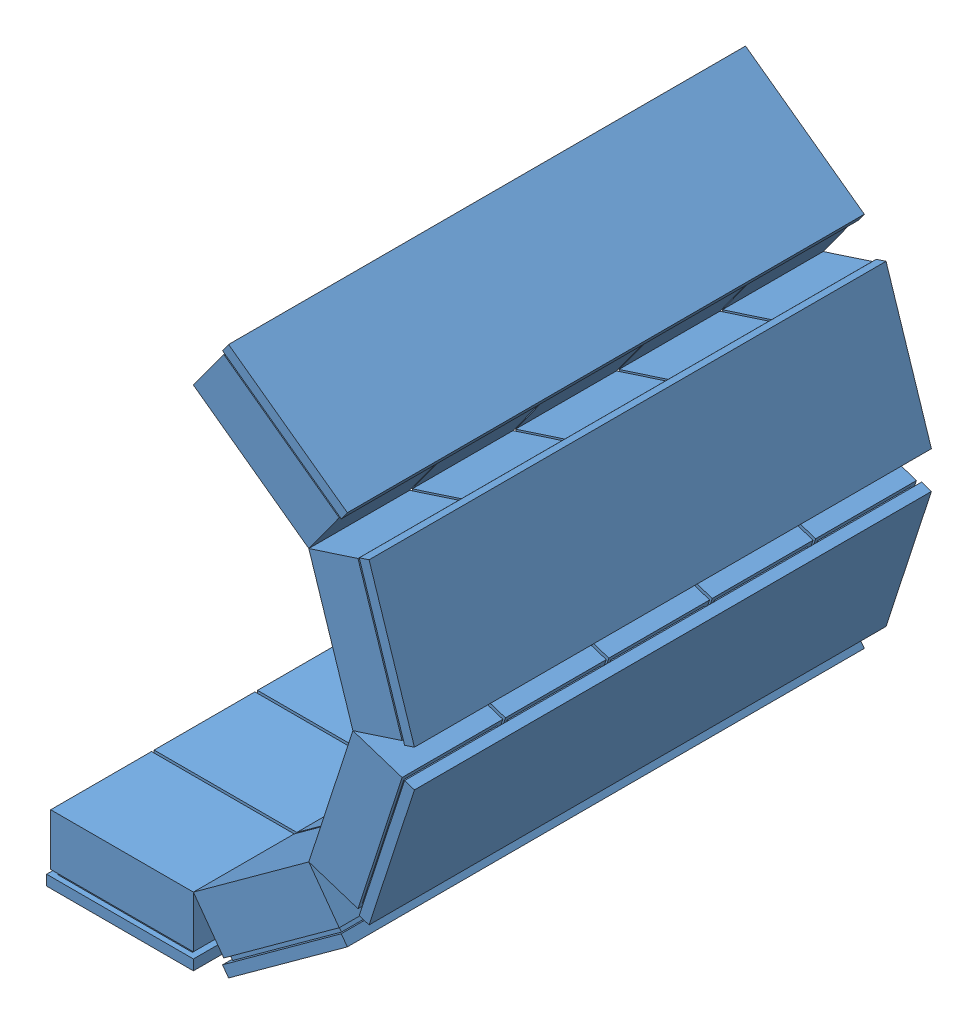
SolidWorks assembly CshapedDetector, configuration Default. Lengths in mm.
Overall size (177.89 270.84 250).
5 component instances, 1 part files, 14 mates.
Components (placement in the parent):
- 1Detector-1: 1Detector [Default] at (91.8512 126.8436 184.2598) size (71 32 250)
- 1Detector-2: 1Detector [Default] at (173.0714 153.2337 184.2598) x (0.809017 0.587785 0) z (0 0 1) size (71 32 250)
- 1Detector-4: 1Detector [Default] at (223.2683 222.3237 184.2598) x (0.309017 0.951057 0) z (0 0 1) size (71 32 250)
- 1Detector-5: 1Detector [Default] at (223.2683 307.7237 184.2598) x (-0.309017 0.951057 0) z (0 0 1) size (71 32 250)
- 1Detector-6: 1Detector [Default] at (173.0714 376.8138 184.2598) x (-0.809017 0.587785 0) z (0 0 1) size (71 32 250)
Mates (geometry in assembly coordinates):
- Coincident2: coincident: line of 1Detector-1 through (126.3512 158.8436 308.2722) axis (0 0 -1); line of 1Detector-2 through (126.3512 158.8436 259.5174) axis (0 0 1)
- Parallel1: parallel: line of 1Detector-1 through (126.3512 158.8436 308.2722) axis (0 0 -1); line of 1Detector-2 through (126.3512 158.8436 259.5174) axis (0 0 1)
- Angle6: planar angle = 2.513274 rad: line of 1Detector-2 through (126.3512 158.8436 308.2722) axis (0.809017 0.587785 0); line of 1Detector-1 through (57.3512 158.8436 308.2722) axis (1 0 0)
- Coincident12: coincident: line of 1Detector-1 through (126.3512 158.8436 308.2722) axis (0 0 -1); plane of 1Detector-2 through (154.2623 179.1222 184.2598) normal (-0.587785 0.809017 0)
- Coincident19: coincident: line of 1Detector-2 through (182.1734 199.4008 308.2722) axis (0 0 -1); line of 1Detector-4 through (182.1734 199.4008 259.5174) axis (0 0 1)
- Coincident22: coincident: point of 1Detector-1; point of 1Detector-2
- Angle9: planar angle = 2.513274 rad: line of 1Detector-4 through (182.1734 199.4008 308.2722) axis (0.309017 0.951057 0); line of 1Detector-2 through (126.3512 158.8436 308.2722) axis (0.809017 0.587785 0)
- Coincident24: coincident: point of 1Detector-2; point of 1Detector-4
- Coincident25: coincident: line of 1Detector-4 through (203.4956 265.0237 308.2722) axis (0 0 -1); line of 1Detector-5 through (203.4956 265.0237 259.5174) axis (0 0 1)
- Angle10: planar angle = 2.513274 rad: line of 1Detector-5 through (203.4956 265.0237 308.2722) axis (-0.309017 0.951057 0); line of 1Detector-4 through (182.1734 199.4008 308.2722) axis (0.309017 0.951057 0)
- Coincident27: coincident: point of 1Detector-4; point of 1Detector-5
- Coincident28: coincident: line of 1Detector-5 through (182.1734 330.6466 308.2722) axis (0 0 -1); line of 1Detector-6 through (182.1734 330.6466 259.5174) axis (0 0 1)
- Angle11: planar angle = 2.513274 rad: line of 1Detector-6 through (182.1734 330.6466 308.2722) axis (-0.809017 0.587785 0); line of 1Detector-5 through (203.4956 265.0237 308.2722) axis (-0.309017 0.951057 0)
- Coincident30: coincident: point of 1Detector-5; point of 1Detector-6
